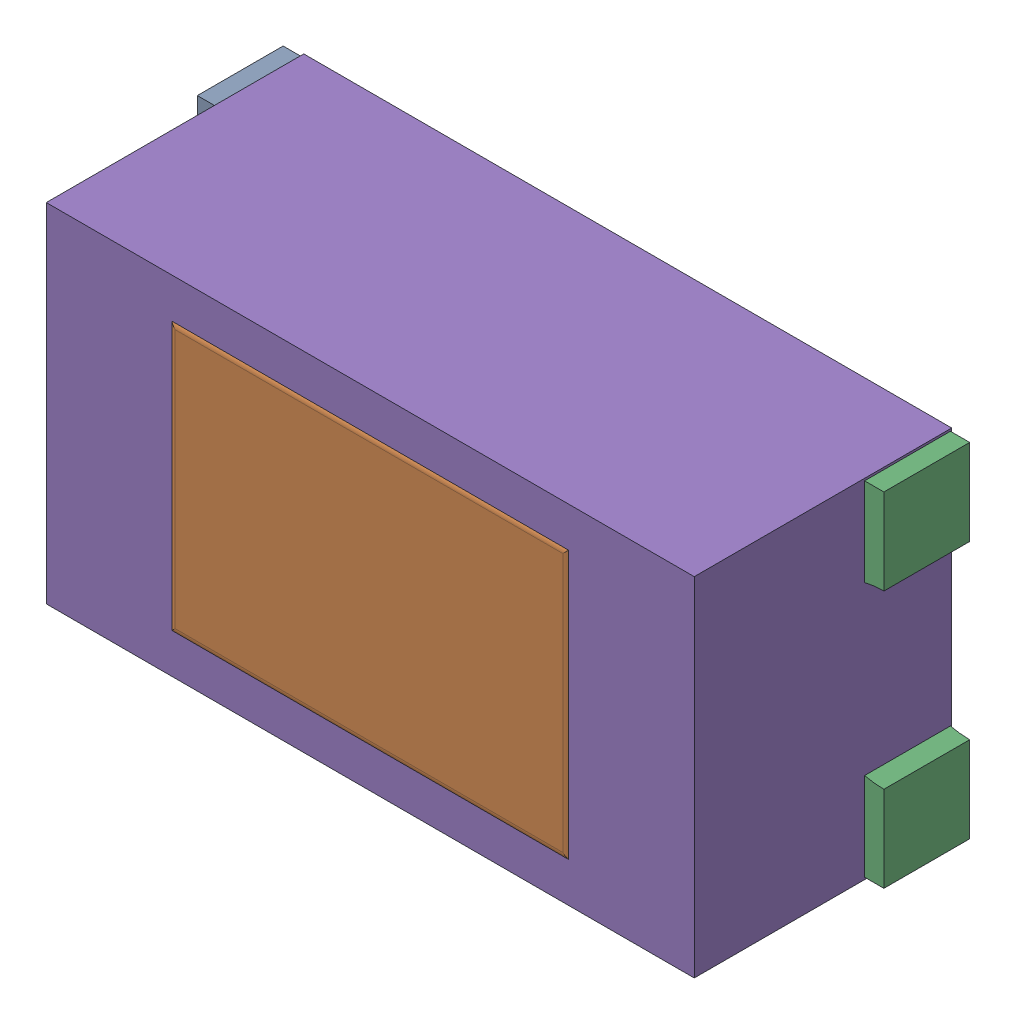
SolidWorks assembly LD2, configuration Default. Lengths in mm.
Overall size (1.61 0.81 0.61).
8 component instances, 6 part files, 0 mates.
Components (placement in the parent):
- LED_0603_GREEN-1: LED_0603_GREEN [Default] at (10.975 4.7749 0.003) x (1 0 0) z (0 0 1) size (1.61 0.81 0.61)
  - User_Library-LED_0603_G_Pocket002-1: User_Library-LED_0603_G_Pocket002 [Default] at origin size (0.41 0.81 0.21)
  - User_Library-LED_0603_G_Pad004-1: User_Library-LED_0603_G_Pad004 [Default] x (1 0 0) z (0 0 -1) size (0.4 0.8 0)
  - User_Library-LED_0603_G_Fillet-1: User_Library-LED_0603_G_Fillet [Default] at origin size (1 0.7 0.4)
  - User_Library-LED_0603_G_Pocket001-1: User_Library-LED_0603_G_Pocket001 [Default] at origin size (0.4 0.8 0.2)
  - User_Library-LED_0603_G_Pad-1: User_Library-LED_0603_G_Pad [Default] at origin size (0.8 0.8 0.2)
- 1737249552-1: 1737249552 [Default] at (10.975 4.775 0) size (1.51 0.81 0.6)
  - Extruded-30-1: Extruded-30 [Default] at origin size (1.51 0.81 0.6)
